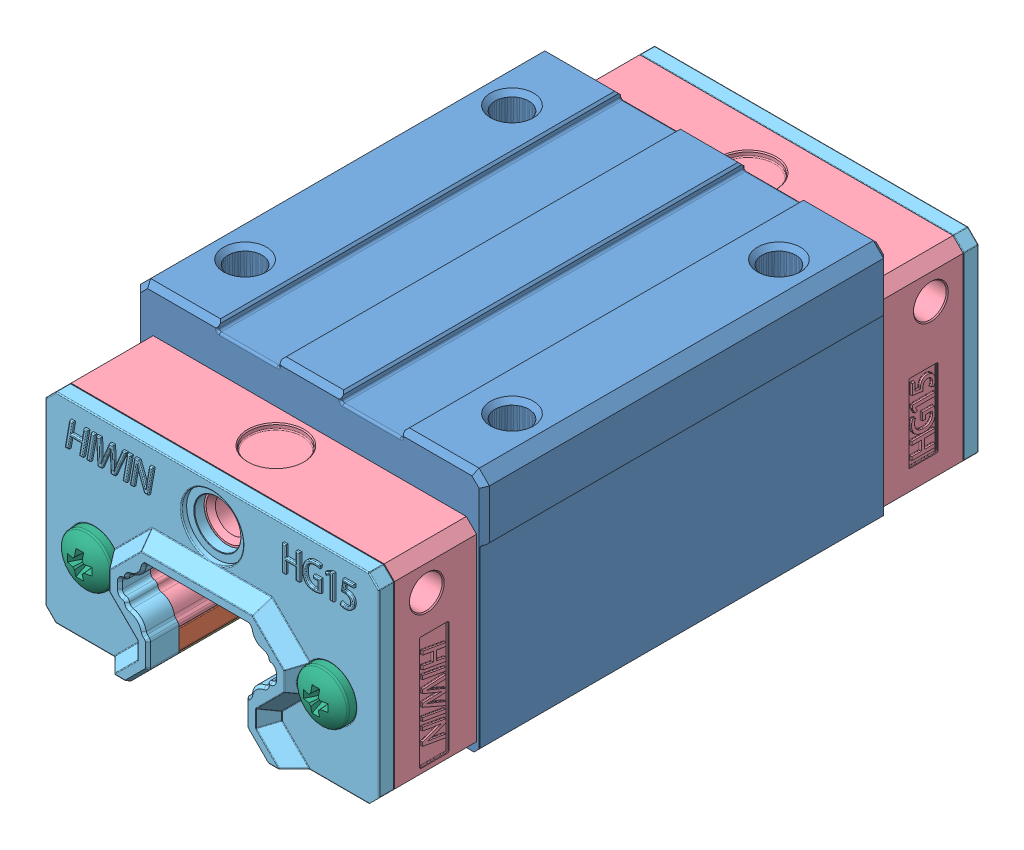
SolidWorks assembly HGH15CA, configuration Default. Lengths in mm.
Overall size (34 23.7 61.49).
11 component instances, 6 part files, 33 mates.
Components (placement in the parent):
- HGH15CA Block-1: HGH15CA Block [HGR15R300CE20] at origin size (34 23.7 39.4)
- HGx15CA Retainer-1: HGx15CA Retainer [HGR15R300CE20] at origin size (26 4 55.4)
- HGx15CA Tiny Red-1: HGx15CA Tiny Red [HGR15R300CE20] at origin size (14.2 1 55.4)
- HGx15CA End Cap-1: HGx15CA End Cap [HGR15R300CE20] at origin size (32.5 19.5 8)
- HGx15CA End Cap-2: HGx15CA End Cap [HGR15R300CE20] x (-1 0 0) z (0 0 -1) size (32.5 19.5 8)
- HGx15CA Seal-1: HGx15CA Seal [HGR15R300CE20] at origin size (32.5 19.5 3)
- HGx15CA Seal-2: HGx15CA Seal [HGR15R300CE20] x (-1 0 0) z (0 0 -1) size (32.5 19.5 3)
- pan head cross recess screw_iso2-1: pan head cross recess screw_iso2 [ISO 7045 - M2.5 x 16 - Z - 16C] at (11.5 11.8 30.8) x (0 0 -1) z (0 -1 0) size (18.05 5 5)
- pan head cross recess screw_iso2-2: pan head cross recess screw_iso2 [ISO 7045 - M2.5 x 16 - Z - 16C] at (-11.5 11.8 30.8) x (0 0 -1) z (0 1 0) size (18.05 5 5)
- pan head cross recess screw_iso2-3: pan head cross recess screw_iso2 [ISO 7045 - M2.5 x 16 - Z - 16C] at (11.5 11.8 -30.8) x (0 0 1) z (0 -1 0) size (18.05 5 5)
- pan head cross recess screw_iso2-4: pan head cross recess screw_iso2 [ISO 7045 - M2.5 x 16 - Z - 16C] at (-11.5 11.8 -30.8) x (0 0 1) z (0 1 0) size (18.05 5 5)
Mates (geometry in assembly coordinates):
- Coincident1: coincident aligned: plane of HGH15CA Block-1 through (0 0 0) normal (0 1 0); plane of HGx15CA Retainer-1 through (0 0 0) normal (0 1 0)
- Coincident2: coincident aligned: plane of HGH15CA Block-1 through (0 0 0) normal (0 0 1); plane of HGx15CA Retainer-1 through (0 0 0) normal (0 0 1)
- Coincident3: coincident aligned: plane of HGH15CA Block-1 through (0 0 0) normal (1 0 0); plane of HGx15CA Retainer-1 through (0 0 0) normal (1 0 0)
- Coincident4: coincident aligned: plane of HGH15CA Block-1 through (0 0 0) normal (0 1 0); plane of HGx15CA Tiny Red-1 through (0 0 0) normal (0 1 0)
- Coincident5: coincident aligned: plane of HGH15CA Block-1 through (0 0 0) normal (0 0 1); plane of HGx15CA Tiny Red-1 through (0 0 0) normal (0 0 1)
- Coincident6: coincident aligned: plane of HGH15CA Block-1 through (0 0 0) normal (1 0 0); plane of HGx15CA Tiny Red-1 through (0 0 0) normal (1 0 0)
- Coincident7: coincident aligned: plane of HGH15CA Block-1 through (0 0 0) normal (0 1 0); plane of HGx15CA End Cap-1 through (0 0 0) normal (0 1 0)
- Coincident8: coincident aligned: plane of HGH15CA Block-1 through (0 0 0) normal (0 0 1); plane of HGx15CA End Cap-1 through (0 0 0) normal (0 0 1)
- Coincident9: coincident aligned: plane of HGH15CA Block-1 through (0 0 0) normal (1 0 0); plane of HGx15CA End Cap-1 through (0 0 0) normal (1 0 0)
- Coincident10: coincident aligned: plane of HGH15CA Block-1 through (0 0 0) normal (0 1 0); plane of HGx15CA End Cap-2 through (0 0 0) normal (0 1 0)
- Coincident11: coincident anti-aligned: plane of HGH15CA Block-1 through (12.9 8.2 -19.7) normal (0 0 -1); plane of HGx15CA End Cap-2 through (-12.9 8.2 -19.7) normal (0 0 1)
- Coincident12: coincident anti-aligned: plane of HGH15CA Block-1 through (0 0 0) normal (1 0 0); plane of HGx15CA End Cap-2 through (0 0 0) normal (-1 0 0)
- Coincident14: coincident aligned: plane of HGH15CA Block-1 through (0 0 0) normal (0 1 0); plane of HGx15CA Seal-1 through (0 0 0) normal (0 1 0)
- Coincident15: coincident aligned: plane of HGH15CA Block-1 through (0 0 0) normal (0 0 1); plane of HGx15CA Seal-1 through (0 0 0) normal (0 0 1)
- Coincident16: coincident aligned: plane of HGH15CA Block-1 through (0 0 0) normal (1 0 0); plane of HGx15CA Seal-1 through (0 0 0) normal (1 0 0)
- Coincident17: coincident aligned: plane of HGH15CA Block-1 through (0 0 0) normal (0 1 0); plane of HGx15CA Seal-2 through (0 0 0) normal (0 1 0)
- Coincident18: coincident anti-aligned: plane of HGx15CA End Cap-2 through (-12.9 8.2 -27.7) normal (0 0 -1); plane of HGx15CA Seal-2 through (5.15 6.4157 -27.7) normal (0 0 1)
- Coincident19: coincident anti-aligned: plane of HGH15CA Block-1 through (0 0 0) normal (1 0 0); plane of HGx15CA Seal-2 through (0 0 0) normal (-1 0 0)
- Concentric1: concentric aligned: cylinder of HGx15CA Seal-1 through (11.5 11.8 28.7) axis (0 0 1) radius 1.5; cylinder of pan head cross recess screw_iso2-1 through (11.5 11.8 56.2) axis (0 0 1) radius 1.25
- Concentric2: concentric aligned: cylinder of HGx15CA Seal-1 through (-11.5 11.8 28.7) axis (0 0 1) radius 1.5; cylinder of pan head cross recess screw_iso2-2 through (-11.5 11.8 56.2) axis (0 0 1) radius 1.25
- Concentric3: concentric aligned: cylinder of HGx15CA Seal-2 through (11.5 11.8 -28.7) axis (0 0 -1) radius 1.5; cylinder of pan head cross recess screw_iso2-3 through (11.5 11.8 -56.2) axis (0 0 -1) radius 1.25
- Concentric4: concentric aligned: cylinder of HGx15CA Seal-2 through (-11.5 11.8 -28.7) axis (0 0 -1) radius 1.5; cylinder of pan head cross recess screw_iso2-4 through (-11.5 11.8 -56.2) axis (0 0 -1) radius 1.25
- Coincident20: coincident anti-aligned: plane of HGx15CA Seal-2 through (11.5 11.8 -28.7) normal (0 0 -1); plane of pan head cross recess screw_iso2-3 through (10.25 11.8 -28.7) normal (0 0 1)
- Coincident21: coincident anti-aligned: plane of HGx15CA Seal-2 through (-11.5 11.8 -28.7) normal (0 0 -1); plane of pan head cross recess screw_iso2-4 through (-10.25 11.8 -28.7) normal (0 0 1)
- Coincident22: coincident anti-aligned: plane of HGx15CA Seal-1 through (11.5 11.8 28.7) normal (0 0 1); plane of pan head cross recess screw_iso2-1 through (12.75 11.8 28.7) normal (0 0 -1)
- Coincident23: coincident anti-aligned: plane of HGx15CA Seal-1 through (-11.5 11.8 28.7) normal (0 0 1); plane of pan head cross recess screw_iso2-2 through (-12.75 11.8 28.7) normal (0 0 -1)
- Parallel1: parallel anti-aligned: plane of HGH15CA Block-1 through (0 0 0) normal (0 1 0); plane of pan head cross recess screw_iso2-1 through (11.5 11.8 30.8) normal (0 -1 0)
- Parallel2: parallel aligned: plane of HGH15CA Block-1 through (0 0 0) normal (0 1 0); plane of pan head cross recess screw_iso2-2 through (-11.5 11.8 30.8) normal (0 1 0)
- Parallel3: parallel anti-aligned: plane of HGH15CA Block-1 through (0 0 0) normal (0 1 0); plane of pan head cross recess screw_iso2-3 through (11.5 11.8 -30.8) normal (0 -1 0)
- Parallel4: parallel aligned: plane of HGH15CA Block-1 through (0 0 0) normal (0 1 0); plane of pan head cross recess screw_iso2-4 through (-11.5 11.8 -30.8) normal (0 1 0)
- Concentric5: concentric anti-aligned: cylinder of HGx15CA Seal-1 through (0 20.05 28.7) axis (0 0 1) radius 2.25; cylinder of ? through (0 20.05 33.5) axis (0 0 -1) radius 2
- Coincident24: coincident anti-aligned: plane of HGx15CA Seal-1 through (0 20.05 28.7) normal (0 0 1); plane of ? through (-2.75 20.05 28.7) normal (0 0 -1)
- Parallel6: parallel aligned: plane of HGH15CA Block-1 through (0 0 0) normal (0 1 0); plane of ? through (0 20.05 39.2) normal (0 1 0)
